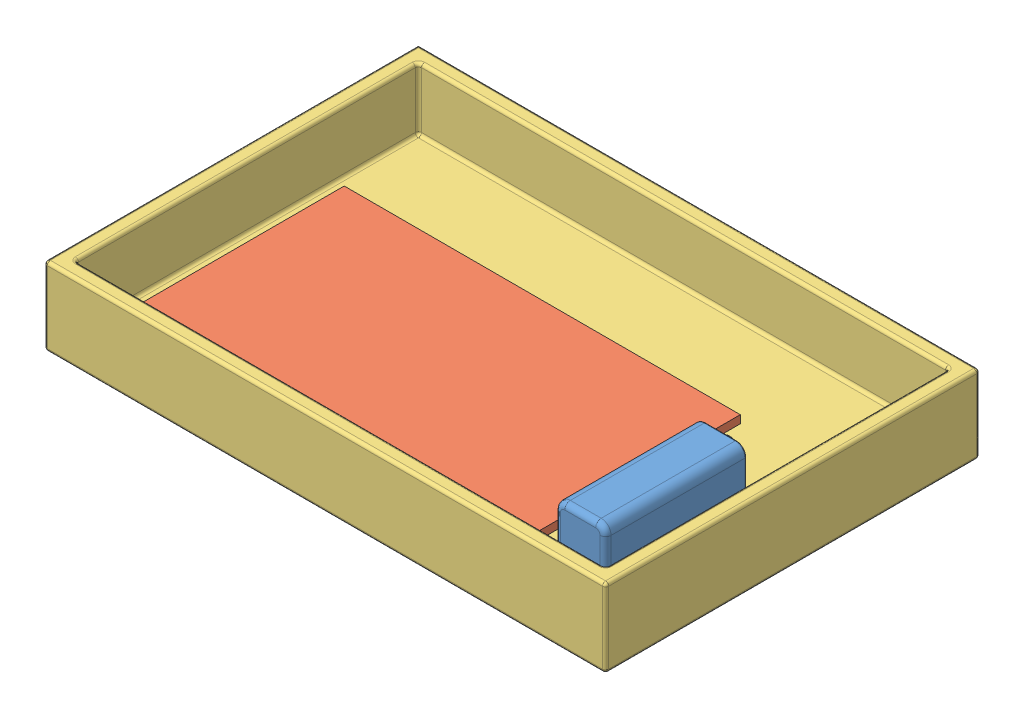
SolidWorks assembly Assem2, configuration Default. Lengths in mm.
Overall size (180 30.91 120).
3 component instances, 3 part files, 6 mates.
Components (placement in the parent):
- Battery 9V-1: Battery 9V [Default] at (176.6958 6.1098 37.3817) x (0 -1 0) z (1 0 0) size (25.91 48.13 16.26)
- PCB substitute block-1: PCB substitute block [Default] at (93.7307 -5.6327 -3.3945) size (127 2.54 76.2)
- case-2: case [Default] at (141.7882 -10.6327 -28.0787) size (180 25 120)
Mates (geometry in assembly coordinates):
- Coincident6: coincident: plane of Battery 9V-1 through (182.4439 -5.6327 -0.3495) normal (0 -1 0); plane of case-2 through (141.7882 -5.6327 -28.0787) normal (0 1 0)
- Distance1: distance = 5 mm: plane of Battery 9V-1 through (198.6999 20.2753 -0.3495) normal (1 0 0); plane of case-2 through (203.6999 -5.6327 -60.1375) normal (-1 0 0)
- Distance2: distance = 5 mm: plane of case-2 through (33.6999 -5.6327 49.8625) normal (0 0 -1); plane of Battery 9V-1 through (198.6999 20.2753 44.8625) normal (0 0 1)
- Distance3: distance = 5 mm: line of PCB substitute block-1 through (38.6999 -3.0927 -31.3375) axis (0 0 1); plane of case-2 through (33.6999 -5.6327 -60.1375) normal (1 0 0)
- Distance4: distance = 5 mm: plane of case-2 through (33.6999 -5.6327 49.8625) normal (0 0 -1); plane of PCB substitute block-1 through (38.6999 -3.0927 44.8625) normal (0 0 1)
- Coincident12: coincident: plane of PCB substitute block-1 through (93.7307 -5.6327 -3.3945) normal (0 -1 0); plane of case-2 through (141.7882 -5.6327 -28.0787) normal (0 1 0)
